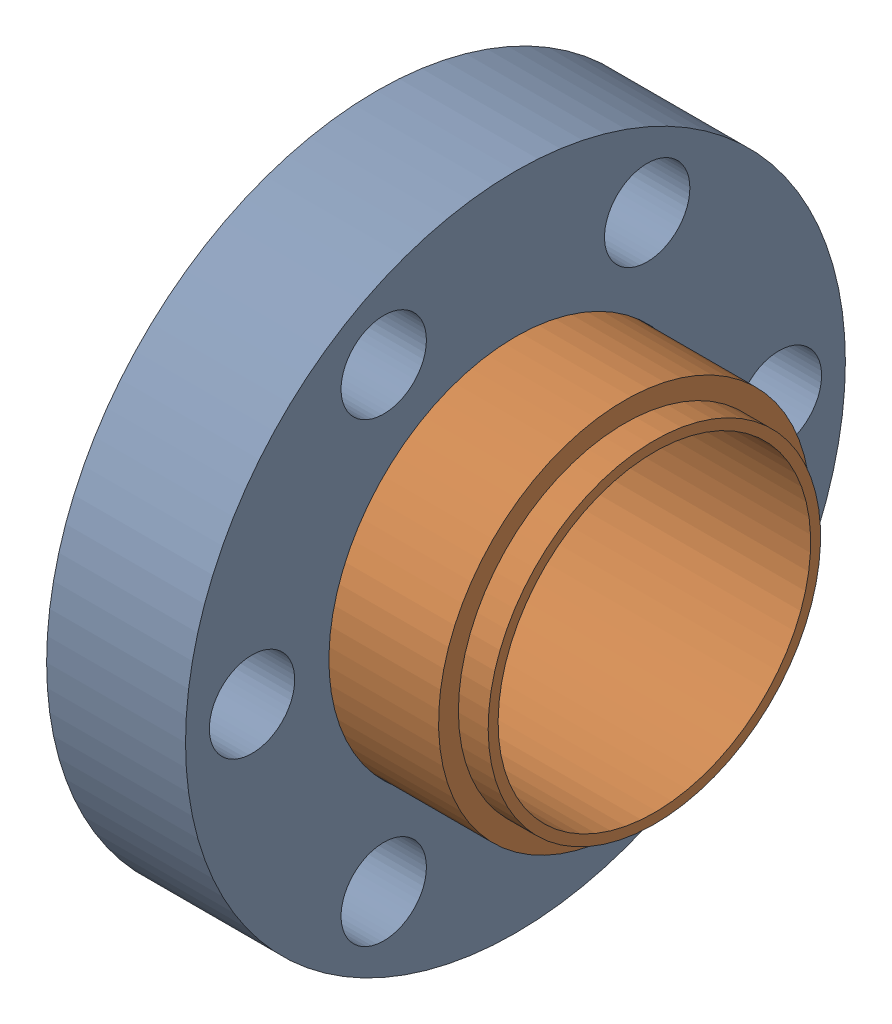
SolidWorks assembly 100004 (1.33 X .75 R), configuration Default. Lengths in mm.
Overall size (14.22 33.78 33.78).
2 component instances, 2 part files, 0 mates.
Components (placement in the parent):
- 100004 (1.33 X .75 REC)-1: 100004 (1.33 X .75 REC) [Default] at origin size (7.11 33.78 33.78)
- 100004 (1.33 X .75 INS)-1: 100004 (1.33 X .75 INS) [Default] at (1.17 0 0) x (1 0 0) z (0 0.470241 -0.882538) size (13.52 21.3 21.3)
